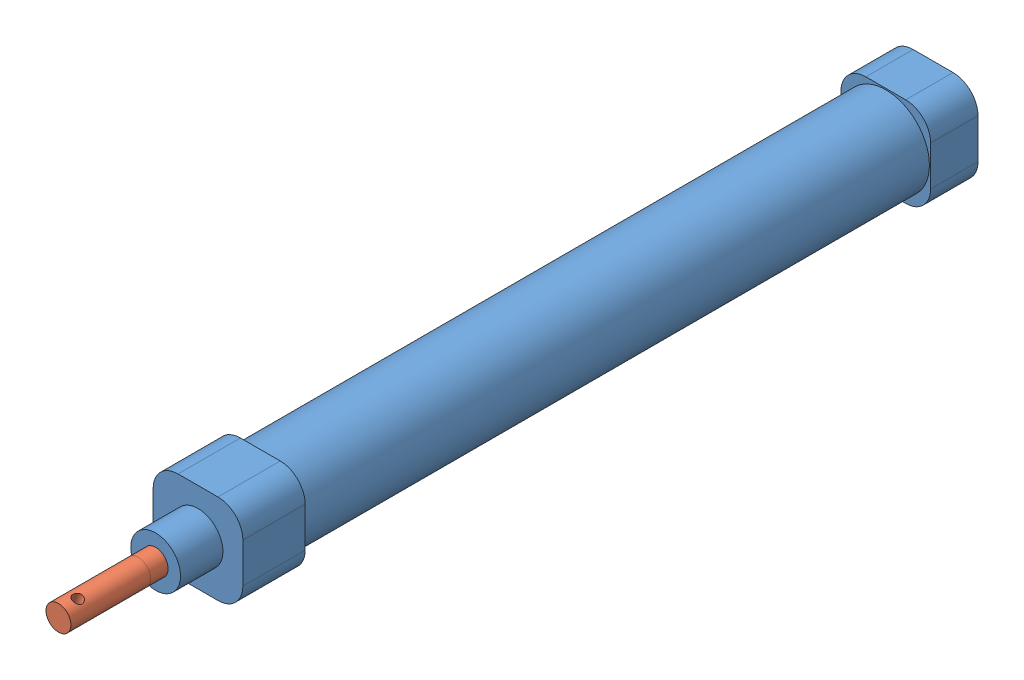
SolidWorks assembly 16x100标准型, configuration 默认. Lengths in mm.
Overall size (18 18 175.5).
2 component instances, 2 part files, 2 mates.
Components (placement in the parent):
- 16x100标准型壳-1: 16x100标准型壳 [默认] at (-1.7591 0.557 78) size (18 18 156)
- 16x100标准型轴-1: 16x100标准型轴 [默认] at (-1.7591 0.557 87.5) x (0.935449 -0.353463 0) z (0 0 1) size (5 5 166)
Mates (geometry in assembly coordinates):
- 同心1: concentric anti-aligned: cylinder of 16x100标准型壳-1 through (-1.7591 0.557 70.9289) axis (0 0 1) radius 2.5; cylinder of 16x100标准型轴-1 through (-1.7591 0.557 237.5) axis (0 0 -1) radius 2.5
- LimitDistance1: limit distance = 19.5 mm aligned: plane of 16x100标准型轴-1 through (-1.7591 0.557 253.5) normal (0 0 1); plane of 16x100标准型壳-1 through (-1.7591 0.557 234) normal (0 0 1)
